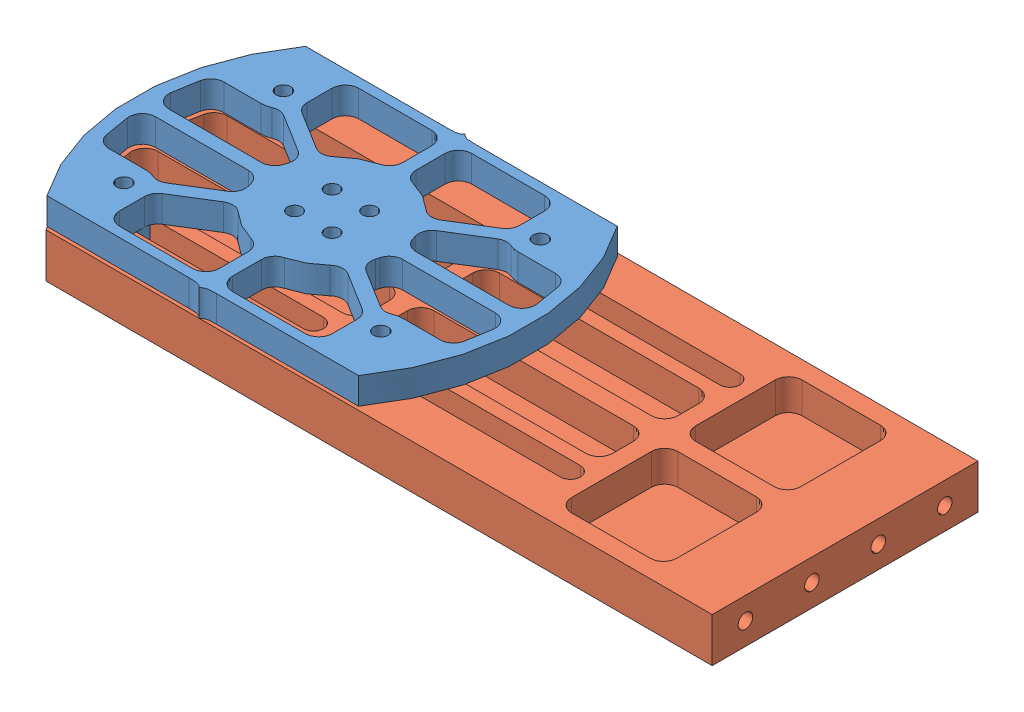
SolidWorks assembly temp, configuration Default. Lengths in mm.
Overall size (160.38 16 60).
2 component instances, 2 part files, 4 mates.
Components (placement in the parent):
- Plate_roll-1: Plate_roll [Default] at (-54.1407 -3.7878 31.1427) size (89.17 10 60)
- Plate_vert_platform-1: Plate_vert_platform [Default] at (106.2421 -13.7878 31.1427) x (0 0 -1) z (1 0 0) size (60 10 160.38)
Mates (geometry in assembly coordinates):
- Совпадение2: coincident anti-aligned: plane of Plate_roll-1 through (-4.1407 -3.7878 1.1427) normal (0 -1 0); plane of Plate_vert_platform-1 through (-4.1424 -3.7878 1.1427) normal (0 1 0)
- Совпадение3: coincident: line of Plate_roll-1 through (-9.5579 2.2122 31.1427) axis (0 -1 0); plane of Plate_vert_platform-1 through (106.2421 -3.7878 31.1427) normal (0 0 1)
- Совпадение4: coincident: line of Plate_roll-1 through (-9.5579 2.2122 -28.8573) axis (0 -1 0); plane of Plate_vert_platform-1 through (106.2421 -3.7878 -28.8573) normal (0 0 -1)
- Концентричный2: concentric anti-aligned: cylinder of Plate_roll-1 through (-41.3579 -7.7878 -16.8573) axis (0 1 0) radius 2.2; cylinder of Plate_vert_platform-1 through (-41.3579 -3.7878 -16.8573) axis (0 -1 0) radius 2.25
